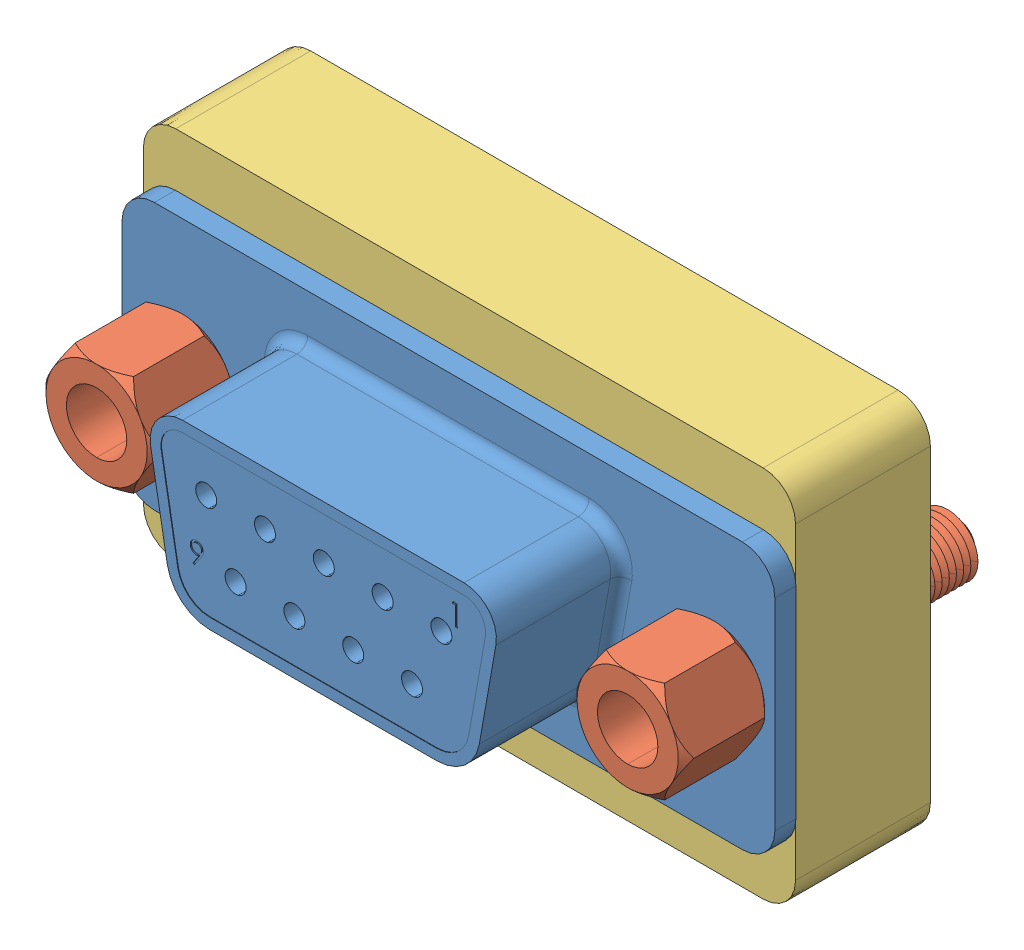
SolidWorks assembly ConnectorAssembly, configuration Default. Lengths in mm.
Overall size (30.73 17.58 17.32).
4 component instances, 3 part files, 7 mates.
Components (placement in the parent):
- FS_DB9_Female_Port-1: FS_DB9_Female_Port [5063N26] at (9.8735 17.9336 25.1411) size (30.73 12.55 16.76)
- FS_DB9_Screw-1: FS_DB9_Screw [Default] at (-2.6265 17.9336 27.6684) x (1 0 0) z (0 -1 0) size (5.5 15.5 5.5)
- FS_DB9_Screw-2: FS_DB9_Screw [Default] at (22.3735 17.9336 27.6684) x (1 0 0) z (0 -1 0) size (5.5 15.5 5.5)
- Part1^ConnectorAssembly-1: Part1^ConnectorAssembly [Default] at (9.8735 17.9336 18.2958) x (1 0 0) z (0 -1 0) size (30.7 6.35 17.58) (virtual)
Mates (geometry in assembly coordinates):
- Coincident1: coincident anti-aligned: plane of FS_DB9_Female_Port-1 through (23.7165 22.6834 25.6364) normal (0 0 1); plane of FS_DB9_Screw-1 through (-5.3761 17.9336 25.6364) normal (0 0 -1)
- Concentric1: concentric anti-aligned: cylinder of FS_DB9_Female_Port-1 through (-2.6265 17.9336 25.6364) axis (0 0 -1) radius 1.524; cylinder of FS_DB9_Screw-1 through (-2.6265 17.9336 29.7004) axis (0 0 1) radius 1.4224
- Coincident2: coincident anti-aligned: plane of FS_DB9_Female_Port-1 through (23.7165 22.6834 25.6364) normal (0 0 1); plane of FS_DB9_Screw-2 through (19.6239 17.9336 25.6364) normal (0 0 -1)
- Concentric2: concentric anti-aligned: cylinder of FS_DB9_Female_Port-1 through (22.3735 17.9336 25.6364) axis (0 0 -1) radius 1.524; cylinder of FS_DB9_Screw-2 through (22.3735 17.9336 29.7004) axis (0 0 1) radius 1.4224
- Coincident3: coincident anti-aligned: plane of FS_DB9_Female_Port-1 through (23.7165 22.6834 24.6458) normal (0 0 -1); plane of Part1^ConnectorAssembly-1 through (9.8735 17.9336 24.6458) normal (0 0 1)
- Coincident4: coincident aligned: line of Part1^ConnectorAssembly-1 through (-2.6265 17.9336 18.2958) axis (0 0 1)
- Concentric3: concentric aligned: cylinder of FS_DB9_Screw-2 through (22.3735 17.9336 29.7004) axis (0 0 1) radius 1.4224; line of Part1^ConnectorAssembly-1 through (22.3735 17.9336 18.2958) axis (0 0 1)
